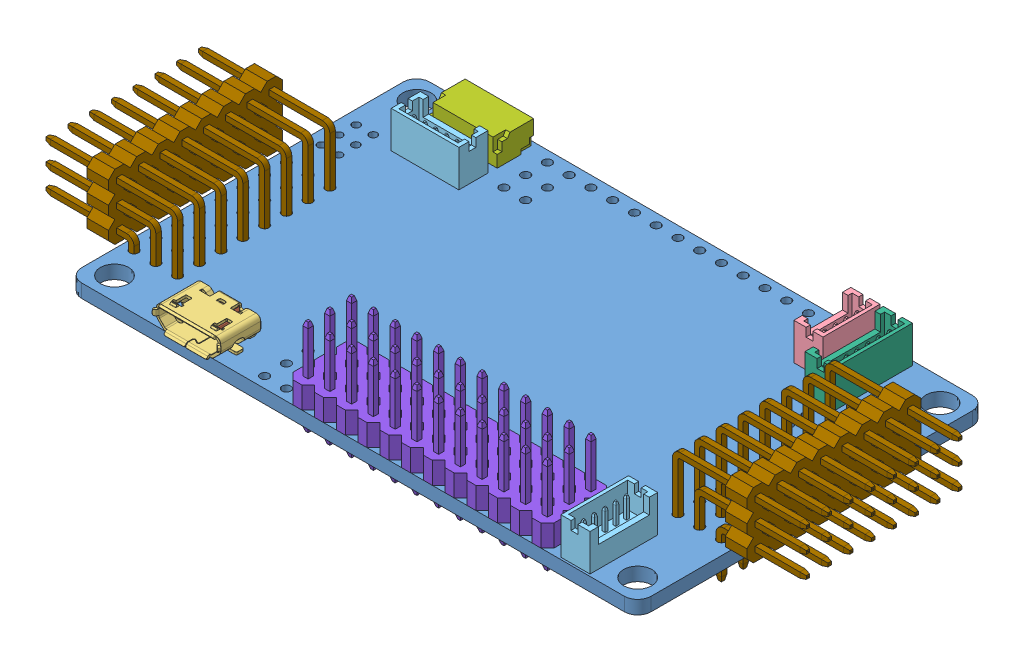
SolidWorks assembly APM_2.6_side, configuration Default. Lengths in mm.
Overall size (83.69 12.26 41.09).
12 component instances, 9 part files, 0 mates.
Components (placement in the parent):
- Copy of APM 2.6 pcb^APM_2.6_side-1: Copy of APM 2.6 pcb^APM_2.6_side [Default] at (-78.5183 46.0489 47.6869) size (66.59 1.57 40.66) (virtual)
- Copy of micro USB^APM_2.6_side-1: Copy of micro USB^APM_2.6_side [Default] at (-116.4897 42.3769 104.3402) size (7.99 2.94 5.43) (virtual)
  - Copy of micro usb02^Copy of micro USB_APM_2.6_side-1: Copy of micro usb02^Copy of micro USB_APM_2.6_side [Default] at (-14.4796 6.4719 -20.7085) size (6.9 2.16 4.2) (virtual)
  - Copy of micro usb^Copy of micro USB_APM_2.6_side-1: Copy of micro usb^Copy of micro USB_APM_2.6_side [Default] at (-14.4796 6.4719 -16.0085) size (7.99 2.94 5.43) (virtual)
- Copy of DF13-4P-1.25DSA^APM_2.6_side-1: Copy of DF13-4P-1.25DSA^APM_2.6_side [Default] at (-91.5721 49.1542 65.8719) size (3.4 6.6 6.65) (virtual)
- Copy of DF13-5P-1.25DSA^APM_2.6_side-1: Copy of DF13-5P-1.25DSA^APM_2.6_side [Default] at (-148.5293 49.1542 55.715) x (0 0 1) z (-1 0 0) size (3.4 6.6 7.9) (virtual)
- Copy of DF13-5P-1.25DSA^APM_2.6_side-2: Copy of DF13-5P-1.25DSA^APM_2.6_side [Default] at (-86.5465 49.1542 70.3859) x (-1 0 0) z (0 0 -1) size (3.4 6.6 7.9) (virtual)
- Copy of DF13-6P-1.25DSA^APM_2.6_side-1: Copy of DF13-6P-1.25DSA^APM_2.6_side [Default] at (-87.7621 49.1542 65.8919) size (3.4 6.6 9.15) (virtual)
- Copy of SM06B-SRSS-TB^APM_2.6_side-1: Copy of SM06B-SRSS-TB^APM_2.6_side [Default] at (-134.7793 47.2687 52.1139) x (-1 0 0) z (0 0 -1) size (8 2.96 4.95) (virtual)
- Copy of HEADER_MALE_3x12^APM_2.6_side-1: Copy of HEADER_MALE_3x12^APM_2.6_side [Default] at (-90.3293 47.6237 81.9769) x (0 0 1) z (-1 0 0) size (7.62 11.18 30.48) (virtual)
- Copy of HEADER_MALE_RA_3x8^APM_2.6_side-1: Copy of HEADER_MALE_RA_3x8^APM_2.6_side [Default] at (-78.4548 48.8937 59.1169) x (0 -1 0) z (0 0 1) size (11.75 15.49 20.32) (virtual)
- Copy of HEADER_MALE_RA_3x8^APM_2.6_side-2: Copy of HEADER_MALE_RA_3x8^APM_2.6_side [Default] at (-145.3838 48.8937 81.9769) x (0 -1 0) z (0 0 -1) size (11.75 15.49 20.32) (virtual)
